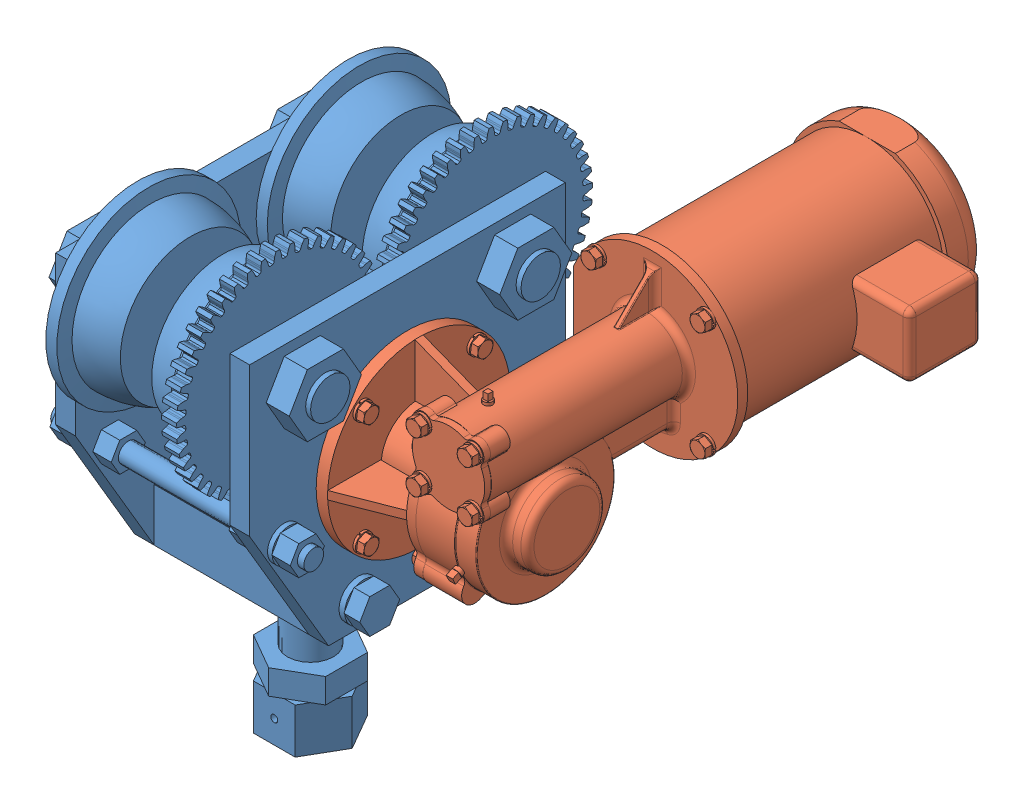
SolidWorks assembly M2630B-RH, configuration Default. Lengths in mm.
Overall size (453.1 492.84 570.37).
2 component instances, 2 part files, 3 mates.
Components (placement in the parent):
- Copy of M2630B-TROLLEY-SECTION^M2630B-RH-1: Copy of M2630B-TROLLEY-SECTION^M2630B-RH [S8x18.4#] at origin size (244.5 492.84 402.11) (virtual)
- Copy of SDT GEAR REDUCER RH M2630 TEMPLATE^M2630B-RH-1: Copy of SDT GEAR REDUCER RH M2630 TEMPLATE^M2630B-RH [Default] at (206.3877 137.4775 0) size (238.76 237.33 457.42) (virtual)
Mates (geometry in assembly coordinates):
- Coincident1: coincident aligned: plane of Copy of M2630B-TROLLEY-SECTION^M2630B-RH-1 through (0 137.4775 0) normal (0 1 0); plane of Copy of SDT GEAR REDUCER RH M2630 TEMPLATE^M2630B-RH-1 through (206.3877 137.4775 0) normal (0 1 0)
- Coincident2: coincident aligned: plane of Copy of SDT GEAR REDUCER RH M2630 TEMPLATE^M2630B-RH-1 through (206.3877 137.4775 0) normal (0 0 1); plane of assembly through (0 0 0) normal (0 0 1)
- Distance1: distance = 17.4625 mm aligned: plane of Copy of SDT GEAR REDUCER RH M2630 TEMPLATE^M2630B-RH-1 through (92.0877 137.4775 0) normal (-1 0 0); plane of Copy of M2630B-TROLLEY-SECTION^M2630B-RH-1 through (74.6252 0 -152.4) normal (-1 0 0)
